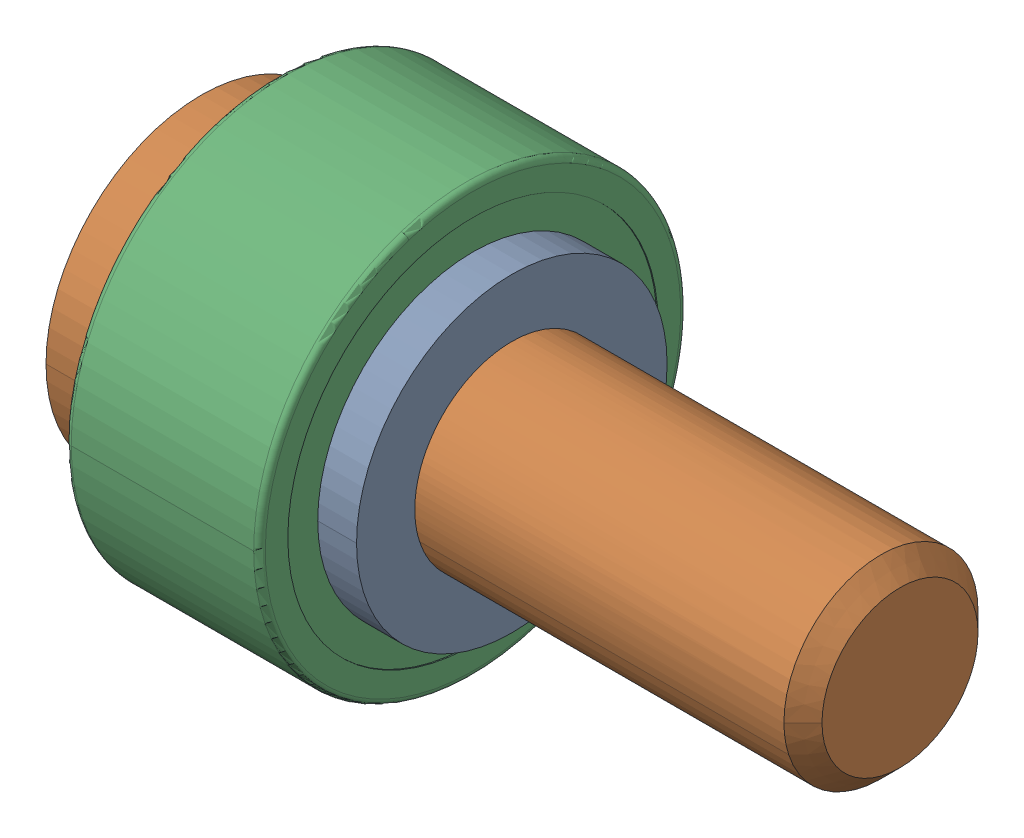
SolidWorks assembly BWP11_6_10, configuration Default. Lengths in mm.
Overall size (18 11 11).
3 component instances, 3 part files, 0 mates.
Components (placement in the parent):
- BWP11_6_10_3-1: BWP11_6_10_3 [Default] at origin size (1 8 8)
- BWP11_6_10_5-1: BWP11_6_10_5 [Default] at origin size (18 8 8)
- BWP11_6_10_7-1: BWP11_6_10_7 [Default] at (2 0 0) size (5 11 11)
